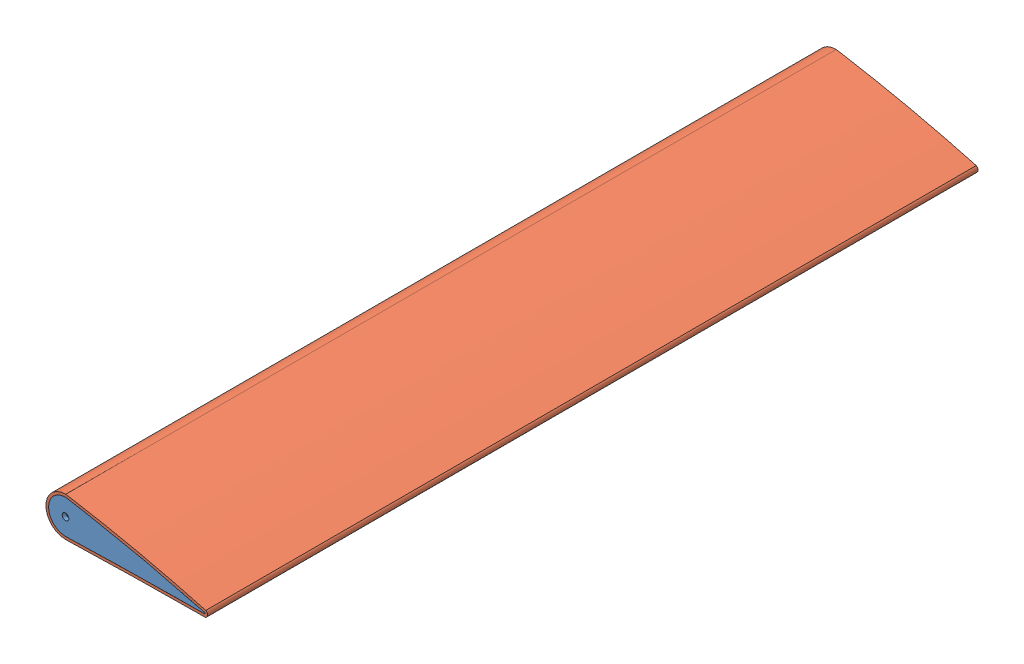
SolidWorks assembly Ailerons(Flaps), configuration Default. Lengths in mm.
Overall size (352.35 44.96 583.27).
8 component instances, 2 part files, 22 mates.
Components (placement in the parent):
- polywoodAileron-1: polywoodAileron [Default] at (-120.9135 207.8922 283.9012) size (350.22 44.96 2.8)
- polywoodAileron-2: polywoodAileron [Default] at (-120.9135 207.8922 672.7012) size (350.22 44.96 2.8)
- polywoodAileron-3: polywoodAileron [Default] at (-120.9135 207.8922 575.5012) size (350.22 44.96 2.8)
- polywoodAileron-4: polywoodAileron [Default] at (-120.9135 207.8922 478.3012) size (350.22 44.96 2.8)
- polywoodAileron-5: polywoodAileron [Default] at (-120.9135 207.8922 381.1012) size (350.22 44.96 2.8)
- AileronEnclosureXPS-1: AileronEnclosureXPS [Default] at (-120.9135 207.8922 674.1012) size (121.94 31.42 583.27)
- polywoodAileron-6: polywoodAileron [Default] at (-120.9135 207.8922 767.1012) size (350.22 44.96 2.8)
- polywoodAileron-7: polywoodAileron [Default] at (-120.9135 207.8922 189.5012) size (350.22 44.96 2.8)
Mates (geometry in assembly coordinates):
- Концентричный1: concentric aligned: cylinder of polywoodAileron-4 through (124.2692 218.3801 479.7012) axis (0 0 -1) radius 2.5; cylinder of polywoodAileron-5 through (124.2692 218.3801 382.5012) axis (0 0 -1) radius 2.5
- Расстояние1: distance = 100 mm anti-aligned: plane of polywoodAileron-4 through (176.672 206.8348 479.7012) normal (0 0 1); plane of polywoodAileron-5 through (176.672 206.8348 379.7012) normal (0 0 -1)
- Расстояние2: distance = 100 mm anti-aligned: plane of polywoodAileron-1 through (176.672 206.8348 282.5012) normal (0 0 -1); plane of polywoodAileron-5 through (176.672 206.8348 382.5012) normal (0 0 1)
- Концентричный2: concentric aligned: cylinder of polywoodAileron-1 through (124.2692 218.3801 285.3012) axis (0 0 -1) radius 2.5; cylinder of polywoodAileron-5 through (124.2692 218.3801 382.5012) axis (0 0 -1) radius 2.5
- Совпадение3: coincident anti-aligned: circle of polywoodAileron-3; cylinder of polywoodAileron-4 through (124.2692 218.3801 479.7012) axis (0 0 -1) radius 2.5
- Расстояние3: distance = 100 mm anti-aligned: plane of polywoodAileron-4 through (176.672 206.8348 476.9012) normal (0 0 -1); plane of polywoodAileron-3 through (176.672 206.8348 576.9012) normal (0 0 1)
- Концентричный3: concentric aligned: cylinder of polywoodAileron-2 through (124.2692 218.3801 674.1012) axis (0 0 -1) radius 2.5; cylinder of polywoodAileron-3 through (124.2692 218.3801 576.9012) axis (0 0 -1) radius 2.5
- Расстояние4: distance = 100 mm anti-aligned: plane of polywoodAileron-2 through (176.672 206.8348 674.1012) normal (0 0 1); plane of polywoodAileron-3 through (176.672 206.8348 574.1012) normal (0 0 -1)
- Концентричный4: concentric aligned: circle of polywoodAileron-2; circle of polywoodAileron-3
- Концентричный5: concentric aligned: circle of polywoodAileron-3; circle of polywoodAileron-4
- Концентричный6: concentric aligned: circle of polywoodAileron-4; circle of polywoodAileron-5
- Концентричный7: concentric aligned: circle of polywoodAileron-1; circle of polywoodAileron-5
- На месте1: in place: plane of polywoodAileron-2 through (176.672 206.8348 674.1012) normal (0 0 1); plane of ? through (0 0 674.1012) normal (0 0 1); moOrthogonalPlaneRef_w of polywoodAileron-2 through (176.672 206.8348 674.1012) normal (0 0 1); plane of ? through (0 0 674.1012) normal (0 1 0); plane of polywoodAileron-2 through (176.672 206.8348 674.1012) normal (0 0 1); plane of ? through (0 0 674.1012) normal (1 0 0); plane of polywoodAileron-2 through (176.672 206.8348 674.1012) normal (0 0 1); unknown of AileronEnclosureXPS-1
- Совпадение10: coincident aligned: plane of polywoodAileron-2; plane of AileronEnclosureXPS-1
- Совпадение11: coincident aligned: moOrthogonalPlaneRef_w of polywoodAileron-2 through (-120.9135 207.8922 674.1012) normal (0 1 0); plane of AileronEnclosureXPS-1 through (-120.9135 207.8922 674.1012) normal (0 1 0)
- Совпадение12: coincident anti-aligned: moOrthogonalPlaneRef_w of polywoodAileron-2 through (-120.9135 207.8922 674.1012) normal (-1 0 0); plane of AileronEnclosureXPS-1 through (-120.9135 207.8922 674.1012) normal (1 0 0)
- Расстояние7: distance = 97.2 mm anti-aligned: plane of polywoodAileron-2 through (176.672 206.8348 671.3012) normal (0 0 -1); plane of polywoodAileron-6 through (176.672 206.8348 768.5012) normal (0 0 1)
- Концентричный8: concentric aligned: cylinder of polywoodAileron-2 through (124.2692 218.3801 674.1012) axis (0 0 -1) radius 2.5; cylinder of polywoodAileron-6 through (124.2692 218.3801 768.5012) axis (0 0 -1) radius 2.5
- Концентричный9: concentric aligned: circle of polywoodAileron-2; circle of polywoodAileron-6
- Расстояние8: distance = 97.2 mm anti-aligned: plane of polywoodAileron-7 through (176.672 206.8348 188.1012) normal (0 0 -1); plane of polywoodAileron-1 through (176.672 206.8348 285.3012) normal (0 0 1)
- Концентричный10: concentric aligned: cylinder of polywoodAileron-1 through (124.2692 218.3801 285.3012) axis (0 0 -1) radius 2.5; cylinder of polywoodAileron-7 through (124.2692 218.3801 190.9012) axis (0 0 -1) radius 2.5
- Концентричный11: concentric aligned: circle of polywoodAileron-1; circle of polywoodAileron-7
